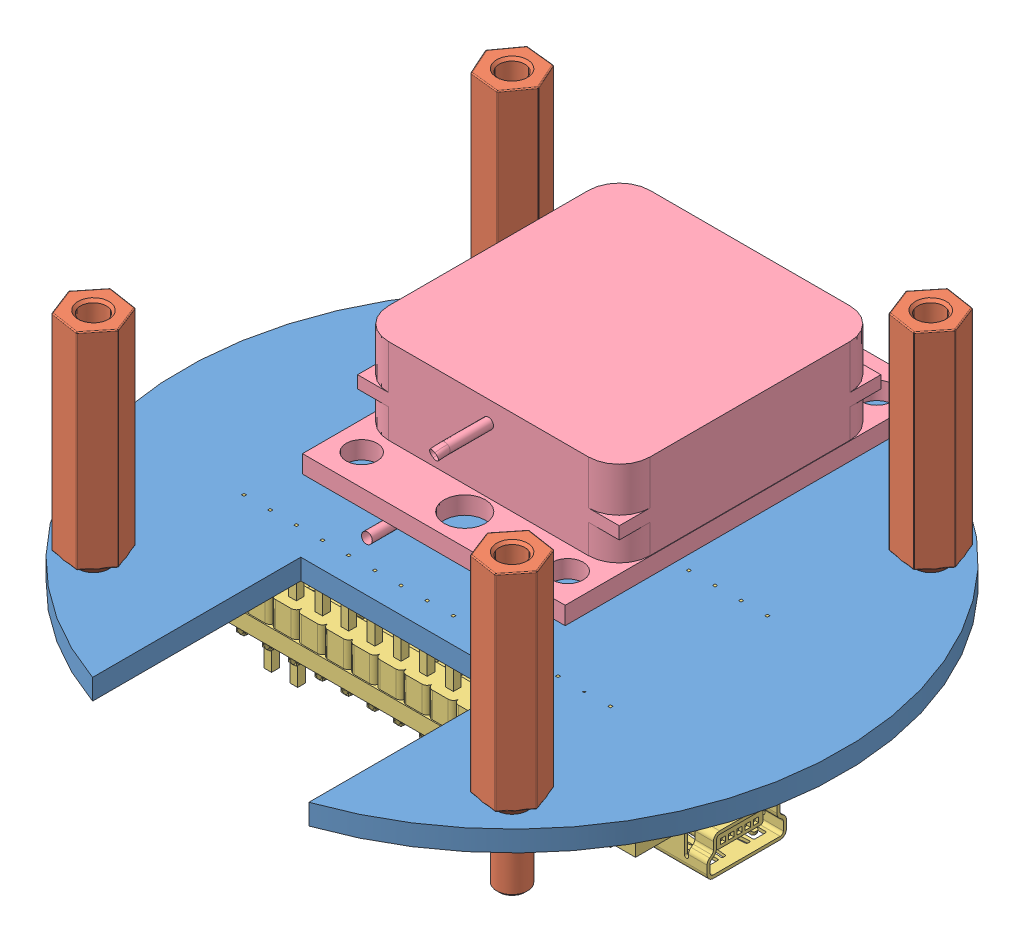
SolidWorks assembly Ensam_pcb_control, configuration Predeterminado. Lengths in mm.
Overall size (64 39.6 62.23).
7 component instances, 4 part files, 10 mates.
Components (placement in the parent):
- power_pcb-2: power_pcb [Predeterminado] at origin size (64 2 62.23)
- separador_bronce_28mm-3: separador_bronce_28mm [Predeterminado] at (-20.5243 3 20.5401) x (0.36247 0 0.931995) z (0 -1 0) size (5.74 5 28)
- separador_bronce_28mm-4: separador_bronce_28mm [Predeterminado] at (20.1173 3 20.5401) x (0.363768 0 0.93149) z (0 -1 0) size (5.74 5 28)
- separador_bronce_28mm-5: separador_bronce_28mm [Predeterminado] at (-20.5243 3 -20.1015) x (-0.408173 0 -0.912905) z (0 -1 0) size (5.74 5 28)
- separador_bronce_28mm-6: separador_bronce_28mm [Predeterminado] at (20.1173 3 -20.1015) x (0.36247 0 0.931995) z (0 -1 0) size (5.74 5 28)
- User Library-arduino_nano-1: User Library-arduino_nano [Predeterminado] at (-18.6955 -6.5 -7.4915) x (1 0 0) z (0 0 -1) size (45 18.6 18)
- gps_module_ublox_neo6mv2-2: gps_module_ublox_neo6mv2 [Predeterminado] at (0.044 8.62 -9.9348) x (-1 0 0) z (0 0 1) size (25.5 12.42 37.54)
Mates (geometry in assembly coordinates):
- Concéntrica8: concentric anti-aligned: cylinder of power_pcb-2 through (-20.5243 2 20.5401) axis (0 -1 0) radius 1.5; cylinder of separador_bronce_28mm-3 through (-20.5243 -5 20.5401) axis (0 1 0) radius 1.5
- Concéntrica9: concentric anti-aligned: cylinder of power_pcb-2 through (20.1173 2 20.5401) axis (0 -1 0) radius 1.5; cylinder of separador_bronce_28mm-4 through (20.1173 -5 20.5401) axis (0 1 0) radius 1.5
- Concéntrica10: concentric anti-aligned: cylinder of power_pcb-2 through (-20.5243 2 -20.1015) axis (0 -1 0) radius 1.5; cylinder of separador_bronce_28mm-5 through (-20.5243 -5 -20.1015) axis (0 1 0) radius 1.5
- Concéntrica11: concentric anti-aligned: cylinder of power_pcb-2 through (20.1173 2 -20.1015) axis (0 -1 0) radius 1.5; cylinder of separador_bronce_28mm-6 through (20.1173 -5 -20.1015) axis (0 1 0) radius 1.5
- Coincidente13: coincident anti-aligned: circle of power_pcb-2; circle of separador_bronce_28mm-3
- Coincidente15: coincident aligned: circle of power_pcb-2; circle of separador_bronce_28mm-5
- Coincidente16: coincident aligned: circle of power_pcb-2; circle of separador_bronce_28mm-4
- Coincidente20: coincident anti-aligned: circle of power_pcb-2; circle of separador_bronce_28mm-6
- Coincidente22: coincident aligned: plane of power_pcb-2 through (-0.2035 2 0.2193) normal (0 1 0); plane of User Library-arduino_nano-1 through (-18.5705 2 7.8735) normal (0 1 0)
- Distancia1: distance = 2.5 mm anti-aligned: plane of power_pcb-2 through (-0.2035 2 0.2193) normal (0 1 0); plane of gps_module_ublox_neo6mv2-2 through (0.044 4.5 -9.9348) normal (0 -1 0)
